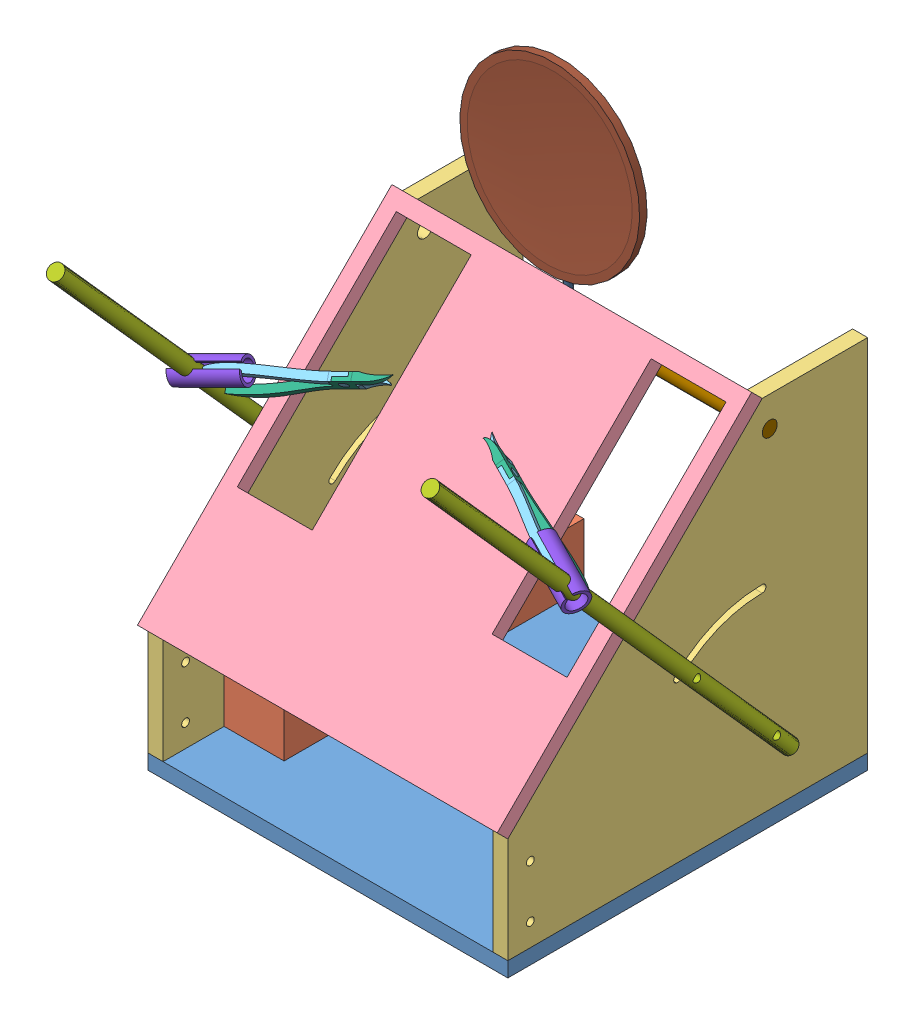
SolidWorks assembly Full Assembly2, configuration Default. Lengths in mm.
Overall size (349.17 481.65 382.39).
19 component instances, 11 part files, 24 mates.
Components (placement in the parent):
- 12x12x0.25in Plywood Panel Bottom-1: 12x12x0.25in Plywood Panel Bottom [Default] at origin size (304.8 12.7 304.8)
- 2x2x11.5in Beam-1: 2x2x11.5in Beam [Default] at (-114.3 38.1 -153.3174) size (50.8 50.8 254)
- 2x2x11.5in Beam-2: 2x2x11.5in Beam [Default] at (114.3 38.1 100.6826) x (-1 0 0) z (0 0 -1) size (50.8 50.8 254)
- 0.25in Plywood Sidepanel-1: 0.25in Plywood Sidepanel [Default] at (139.7 165.1 0) size (12.7 304.8 304.8)
- 0.25in Plywood Sidepanel-2: 0.25in Plywood Sidepanel [Default] at (-152.4 165.1 0) size (12.7 304.8 304.8)
- 12x12x0.25in Plywood Panel-4: 12x12x0.25in Plywood Panel [Default] at (0 209.7369 44.6369) x (1 0 0) z (0 -0.707107 0.707107) size (304.8 12.7 304.8)
- Clippers-1: Clippers [Default] at (86.0172 407.0229 80.8875) x (0.902789 -0.286314 0.32093) z (0 -0.746204 -0.665717) size (125.04 9.82 49.06)
  - Clipper-1: Clipper [Default] at (16.3733 71.2892 99.5799) size (124.46 9.76 31.51)
  - Clipper2-1: Clipper2 [Default] at (16.3733 71.2892 99.5799) x (0.999819 0 0.019033) z (0.019033 0 -0.999819) size (124.46 9.76 31.51)
- ClipperHolderUpright-1: ClipperHolderUpright [Default] at (158.75 57.2464 -80.0354) x (1 0 0) z (0 -0.665717 0.746204) size (12.7 457.2 12.7)
- ClipperHolderTube-1: ClipperHolderTube [Default] at (124.3537 279.0067 95.8461) x (0.430084 0.601002 -0.673665) z (0.902789 -0.286314 0.32093) size (20.32 20.32 50.8)
- ClipperHolderTube-2: ClipperHolderTube [Default] at (-124.3537 279.0067 95.8461) x (0.430084 -0.601002 0.673665) z (-0.902789 -0.286314 0.32093) size (20.32 20.32 50.8)
- Clippers-2: Clippers [Default] at (-24.6965 321.3329 176.9376) x (-0.902789 -0.286314 0.32093) z (0 -0.746204 -0.665717) size (125.04 9.82 49.06)
  - Clipper-1: Clipper [Default] at (16.3733 71.2892 99.5799) size (124.46 9.76 31.51)
  - Clipper2-1: Clipper2 [Default] at (16.3733 71.2892 99.5799) x (0.999819 0 0.019033) z (0.019033 0 -0.999819) size (124.46 9.76 31.51)
- ClipperHolderUpright-2: ClipperHolderUpright [Default] at (-158.75 57.2464 -80.0354) x (-1 0 0) z (0 0.665717 -0.746204) size (12.7 457.2 12.7)
- MirrorHorizontalRod-1: MirrorHorizontalRod [Default] at (-25.4 292.1 -69.4761) x (0 0.036189 0.999345) z (0 0.999345 -0.036189) size (12.7 177.8 12.7)
- MirrorVerticalRod-1: MirrorVerticalRod [Default] at (-19.05 285.7542 -69.2463) x (0.960449 0.010077 0.278275) z (-0.278457 0.034758 0.959819) size (6.35 152.4 6.35)
- Mirror-1: Mirror [Default] at (-19.05 405.268 -60.8659) x (-1 0 0) z (0 -0.036189 -0.999345) size (152.4 152.4 31.75)
Mates (geometry in assembly coordinates):
- Coincident3: coordinate: point of 12x12x0.25in Plywood Panel Bottom-1; point of assembly
- Coincident4: coincident anti-aligned: plane of 12x12x0.25in Plywood Panel Bottom-1 through (0 12.7 0) normal (0 1 0); plane of 2x2x11.5in Beam-1 through (-139.7 12.7 100.6826) normal (0 -1 0)
- Coincident11: coincident: point of 12x12x0.25in Plywood Panel Bottom-1; point of 0.25in Plywood Sidepanel-1
- Coincident12: coincident: point of 12x12x0.25in Plywood Panel Bottom-1; point of 0.25in Plywood Sidepanel-1
- Coincident13: coincident anti-aligned: plane of 12x12x0.25in Plywood Panel Bottom-1 through (0 12.7 0) normal (0 1 0); plane of 0.25in Plywood Sidepanel-1 through (152.4 12.7 152.4) normal (0 -1 0)
- Coincident14: coincident: point of 0.25in Plywood Sidepanel-2; point of 12x12x0.25in Plywood Panel-4
- Coincident15: coincident: point of 0.25in Plywood Sidepanel-1; point of 12x12x0.25in Plywood Panel-4
- Coincident16: coincident: line of 0.25in Plywood Sidepanel-2 through (-152.4 317.5 -63.1261) axis (0 -0.707107 0.707107); plane of 12x12x0.25in Plywood Panel-4 through (0 209.7369 44.6369) normal (0 -0.707107 -0.707107)
- Coincident17: coincident aligned: line of 2x2x11.5in Beam-1 through (-139.7 12.7 100.6826) axis (0 0 -1); line of 0.25in Plywood Sidepanel-2 through (-139.7 12.7 152.4) axis (0 0 -1)
- Coincident22: coincident: cylinder of ClipperHolderUpright-1 through (158.75 398.4109 224.3306) axis (0 -0.746204 -0.665717) radius 6.35; line of ClipperHolderTube-1 through (165.0965 273.3192 113.0129) axis (0 0.746204 0.665717)
- Coincident23: coincident: cylinder of ClipperHolderUpright-1 through (158.75 398.4109 224.3306) axis (0 -0.746204 -0.665717) radius 6.35; line of ClipperHolderTube-1 through (152.4035 275.5786 114.4658) axis (0 -0.746204 -0.665717)
- Concentric1: concentric anti-aligned: cylinder of 0.25in Plywood Sidepanel-1 through (238.5265 76.2 -63.1261) axis (-1 0 0) radius 3.175; cylinder of ClipperHolderUpright-1 through (152.4 76.2 -63.1261) axis (1 0 0) radius 3.175
- Tangent5: tangent anti-aligned: plane of 0.25in Plywood Sidepanel-1 through (152.4 165.1 0) normal (1 0 0); cylinder of ClipperHolderUpright-1 through (158.75 398.4109 224.3306) axis (0 -0.746204 -0.665717) radius 6.35
- Parallel1: parallel: line of Clippers-1/Clipper-1 through (151.2694 267.4424 108.7455) axis (0.430084 0.601002 -0.673665); plane of ClipperHolderUpright-1 through (158.75 398.4109 224.3306) normal (0 0.746204 0.665717)
- Parallel4: parallel anti-aligned: line of Clippers-1/Clipper-1 through (64.9791 291.5577 70.2684) axis (0.902789 -0.286314 0.32093); line of ClipperHolderTube-1 through (152.4035 275.5786 114.4658) axis (-0.902789 0.286314 -0.32093)
- Tangent8: tangent: line of Clippers-1/Clipper-1 through (151.2694 267.4424 108.7455) axis (0.430084 0.601002 -0.673665); cylinder of ClipperHolderUpright-1 through (158.75 398.4109 224.3306) axis (0 -0.746204 -0.665717) radius 6.35
- Coincident36: coincident: plane of Clippers-1/Clipper-1 through (71.5587 287.1676 65.6507) normal (0.430084 0.601002 -0.673665); line of ClipperHolderTube-1 through (125.4462 287.8739 100.6839) axis (0 -0.746204 -0.665717)
- Tangent10: tangent: curve of Clippers-1/Clipper-1; line of ClipperHolderTube-1 through (154.5883 276.6518 109.2773) axis (-0.902789 0.286314 -0.32093)
- Concentric2: concentric aligned: cylinder of 0.25in Plywood Sidepanel-1 through (238.5265 292.1 -69.4761) axis (-1 0 0) radius 6.35; cylinder of MirrorHorizontalRod-1 through (152.4 292.1 -69.4761) axis (-1 0 0) radius 6.35
- Concentric3: concentric anti-aligned: cylinder of MirrorHorizontalRod-1 through (-19.05 285.7542 -69.2463) axis (0 0.999345 -0.036189) radius 3.175; cylinder of MirrorVerticalRod-1 through (-19.05 438.0543 -74.7616) axis (0 -0.999345 0.036189) radius 3.175
- Tangent11: tangent aligned: cylinder of MirrorHorizontalRod-1 through (152.4 292.1 -69.4761) axis (-1 0 0) radius 6.35; plane of MirrorVerticalRod-1 through (-19.05 285.7542 -69.2463) normal (0 -0.999345 0.036189)
- Coincident37: coincident aligned: plane of 0.25in Plywood Sidepanel-1 through (152.4 165.1 0) normal (1 0 0); plane of MirrorHorizontalRod-1 through (152.4 292.1 -69.4761) normal (1 0 0)
- Concentric4: concentric anti-aligned: cylinder of MirrorVerticalRod-1 through (-19.05 438.0543 -74.7616) axis (0 -0.999345 0.036189) radius 3.175; cylinder of Mirror-1 through (-19.05 398.4625 -73.3278) axis (0 0.999345 -0.036189) radius 3.175
- Perpendicular1: perpendicular: plane of 0.25in Plywood Sidepanel-2 through (-139.7 165.1 0) normal (1 0 0); plane of Mirror-1 through (57.15 405.268 -60.8659) normal (0 -0.036189 -0.999345)
